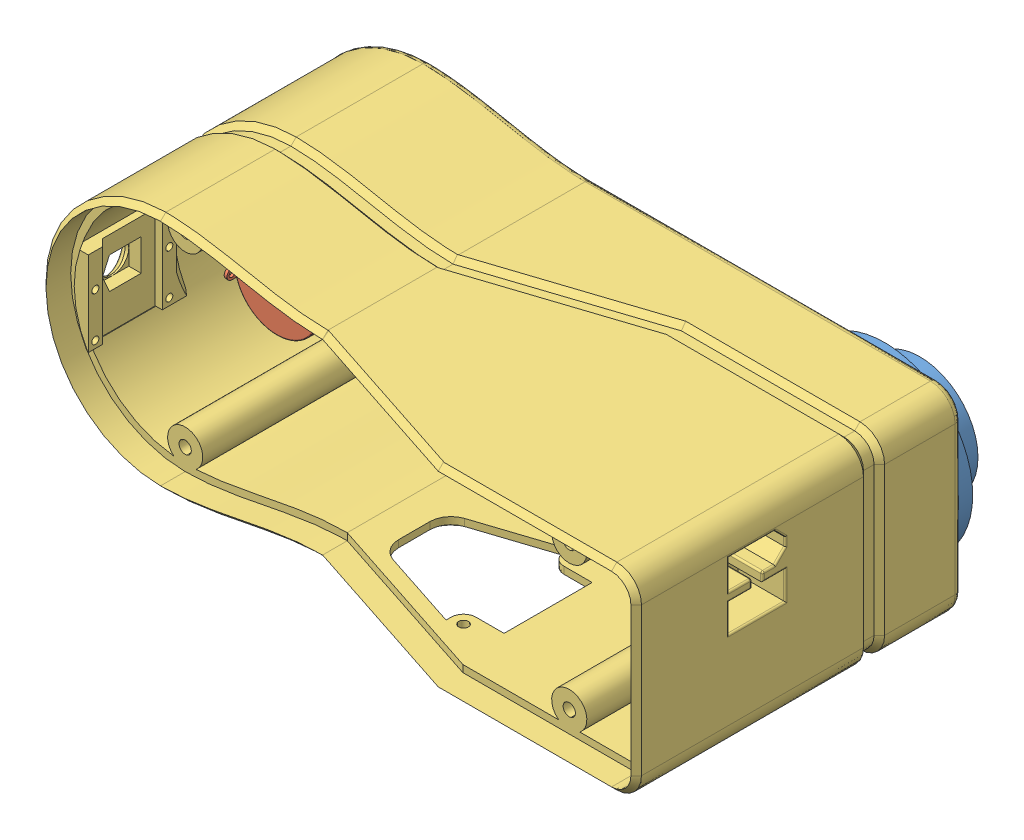
SolidWorks assembly Side_Assem_Left, configuration Default. Lengths in mm.
Overall size (185 73.69 116).
5 component instances, 3 part files, 8 mates.
Components (placement in the parent):
- motor_holder_r0.4-1: motor_holder_r0.4 [Default] at (-49.6677 4.5588 -35.0076) x (0 0 -1) z (1 0 0) size (14 50 50)
- Motor_25x55_gear-1: Motor_25x55_gear [Default] at (-49.6677 4.5588 -44.5076) x (-1 0 0) z (0 0 -1) size (25 25 71.85)
- Motor_25x55_gear-2: Motor_25x55_gear [Default] at (75.3323 4.5588 -44.5076) x (-1 0 0) z (0 0 -1) size (25 25 71.85)
- motor_holder_r0.4-2: motor_holder_r0.4 [Default] at (75.3323 4.5588 -35.0076) x (0 0 -1) z (1 0 0) size (14 50 50)
- Side_Left-1: Side_Left [Default] at (11.3323 4.5588 -35.0076) size (185 73.69 93.44)
Mates (geometry in assembly coordinates):
- Concentric1: concentric anti-aligned: cylinder of motor_holder_r0.4-1 through (-49.6677 4.5588 -49.0076) axis (0 0 1) radius 16.5; cylinder of Motor_25x55_gear-1 through (-49.6677 4.5588 -23.5076) axis (0 0 -1) radius 12.5
- Coincident1: coincident anti-aligned: circle of motor_holder_r0.4-1; plane of Motor_25x55_gear-1 through (-49.6677 4.5588 -46.5076) normal (0 0 -1)
- Concentric2: concentric aligned: cylinder of Motor_25x55_gear-1 through (-49.6677 4.5588 8.4924) axis (0 0 -1) radius 12.05; cylinder of Side_Left-1 through (-49.6677 4.5588 50.4924) axis (0 0 -1) radius 13
- Coincident2: coincident anti-aligned: plane of motor_holder_r0.4-1 through (-49.6677 4.5588 -35.0076) normal (0 0 1); plane of Side_Left-1 through (11.3323 4.5588 -35.0076) normal (0 0 -1)
- Concentric3: concentric aligned: cylinder of motor_holder_r0.4-1 through (-64.1634 19.0545 -39.0076) axis (0 0 -1) radius 1.7; cylinder of Side_Left-1 through (-64.1634 19.0545 50.4924) axis (0 0 -1) radius 1.25
- Concentric4: concentric aligned: cylinder of motor_holder_r0.4-1 through (-35.172 -9.9369 -39.0076) axis (0 0 -1) radius 1.7; cylinder of Side_Left-1 through (-35.172 -9.9369 50.4924) axis (0 0 -1) radius 1.25
- Concentric5: concentric aligned: cylinder of motor_holder_r0.4-1 through (-58.1677 4.5588 -49.0076) axis (0 0 -1) radius 1.7; cylinder of Motor_25x55_gear-1 through (-58.1677 4.5588 -46.5076) axis (0 0 -1) radius 1.25
- Concentric6: concentric aligned: circle of motor_holder_r0.4-1; cylinder of Motor_25x55_gear-1 through (-41.1677 4.5588 -46.5076) axis (0 0 -1) radius 1.25
